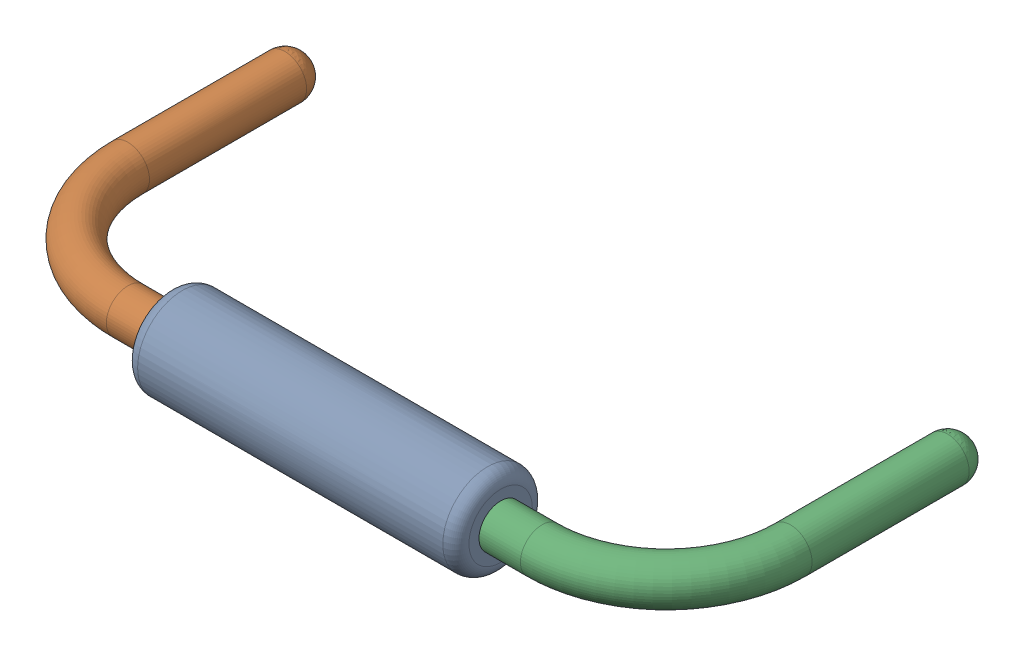
SolidWorks assembly R4, configuration Défaut. Lengths in mm.
Overall size (10.82 1.37 5.33).
4 component instances, 3 part files, 0 mates.
Components (placement in the parent):
- Open CASCADE STEP translator 6.8 1.10.1-1: Open CASCADE STEP translator 6.8 1.10.1 [Défaut] at origin size (10.82 1.37 5.33)
  - Body_1_7-1: Body_1_7 [Défaut] at origin size (5.08 1.37 1.37)
  - Pin_1_4-1: Pin_1_4 [Défaut] at origin size (3.2 0.66 4.98)
  - Pin_2_4-1: Pin_2_4 [Défaut] at (20.32 0 0) x (-1 0 0) z (0 0 1) size (3.2 0.66 4.98)
